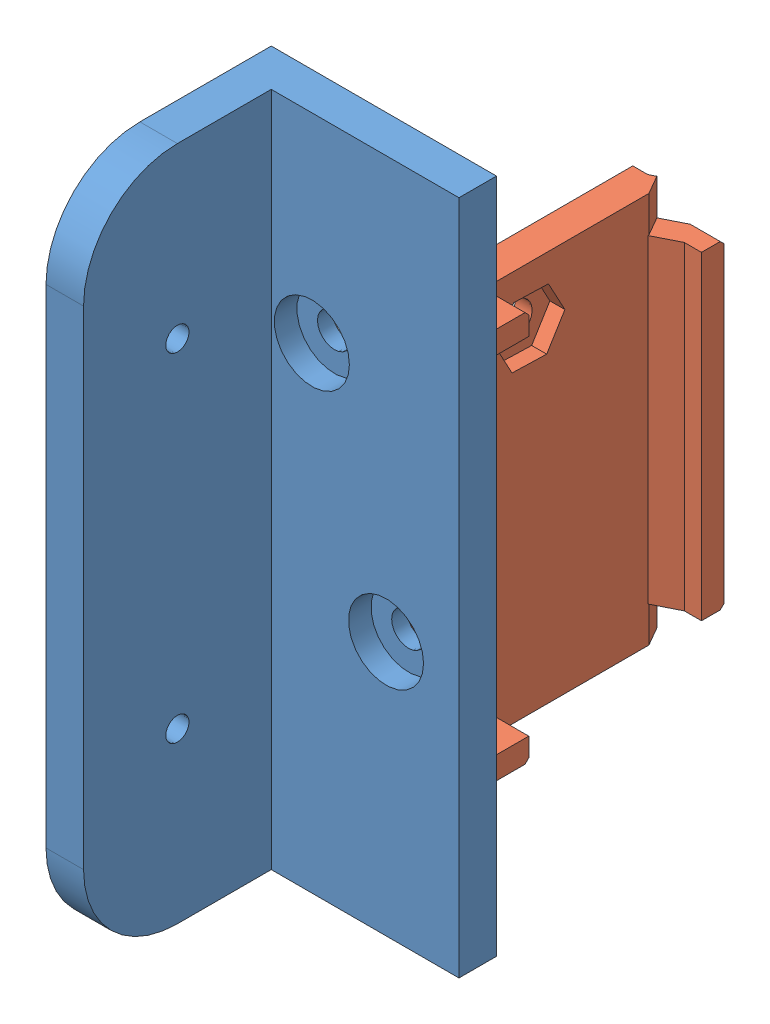
SolidWorks assembly Assemblage1, configuration Défaut. Lengths in mm.
Overall size (30 90 80.55).
2 component instances, 2 part files, 3 mates.
Components (placement in the parent):
- support camera-1: support camera [Défaut] at (-16.0378 -0.5319 90) size (30 90 30)
- support mannfrotto-1: support mannfrotto [Défaut] at (-17.5378 -19.4319 70.3514) x (0 0 1) z (-1 0 0) size (42.3 52.1 9.75)
Mates (geometry in assembly coordinates):
- Coïncidente1: coincident: plane of support camera-1 through (-27.2878 44.5181 104.75) normal (-1 0 0); plane of support mannfrotto-1 through (-27.2878 6.6181 51.6014) normal (-1 0 0)
- Parallèle1: parallel: plane of support camera-1 through (-16.0378 -0.5319 99.75) normal (0 0 -1); plane of support mannfrotto-1 through (-20.5378 6.6181 91.5014) normal (0 0 1)
- Coïncidente3: coincident aligned: plane of support camera-1 through (2.7122 -45.4819 104.75) normal (0 -1 0); plane of support mannfrotto-1 through (-22.1855 -45.4819 70.3514) normal (0 -1 0)
